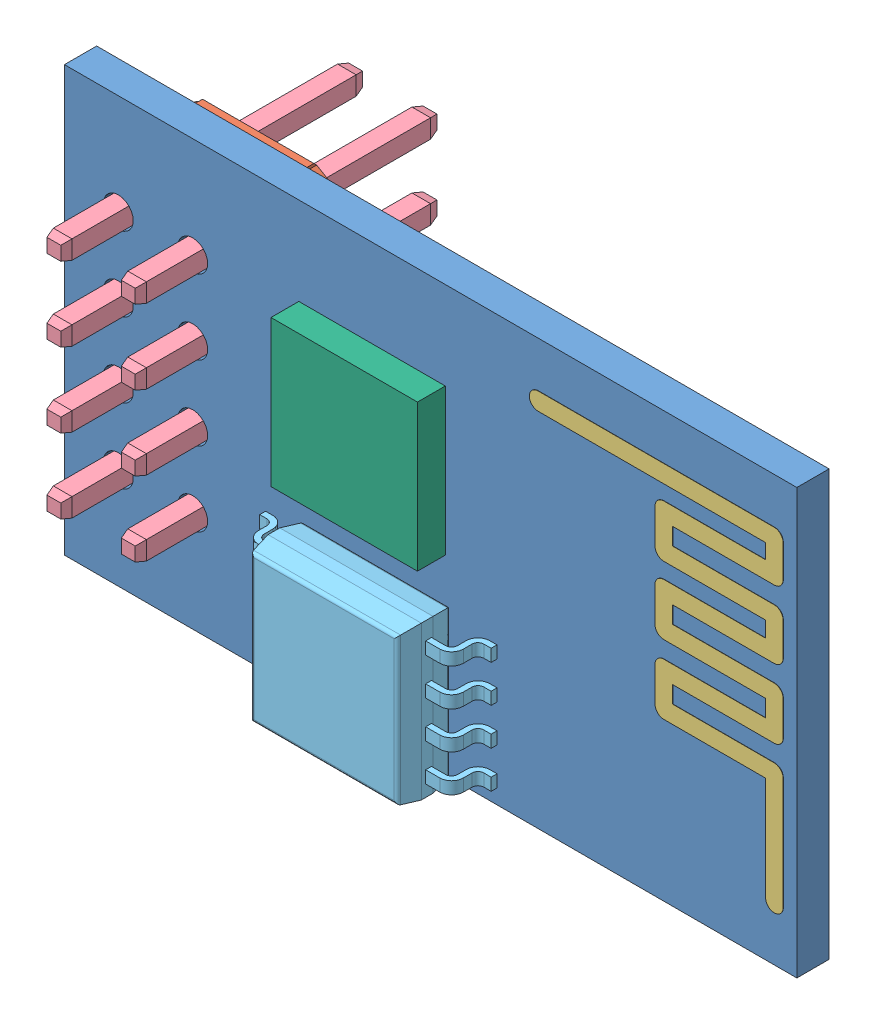
SolidWorks assembly ESP8266-ESP01, configuration Default. Lengths in mm.
Overall size (25 14.5 10.3).
15 component instances, 6 part files, 0 mates.
Components (placement in the parent):
- ESP8266-ESP01.STEP-1: ESP8266-ESP01.STEP [Default] at origin size (25 14.5 10.3)
  - ESP8266-ESP01.stp.STEP-1: ESP8266-ESP01.stp.STEP [Default] at origin size (25 14.5 10.3)
    - Platine.stp.STEP-1: Platine.stp.STEP [Default] at origin size (25 14.5 1.1)
    - PinSockel.stp.STEP-1: PinSockel.stp.STEP [Default] at (1.8391 11.06 0) x (1 0 0) z (0 0 -1) size (5 10.16 2.5)
    - PCB_Antenna.stp.STEP-1: PCB_Antenna.stp.STEP [Default] at (1 16 0.81) x (0 -1 0) z (-1 0 0) size (11.4 0.04 8.67)
    - Pin_Stiftleiste.stp.STEP-1: Pin_Stiftleiste.stp.STEP [Default] at (1.8391 3.44 0) x (-1 0 0) z (0 0 -1) size (0.64 0.64 10.3)
    - Pin_Stiftleiste.stp.STEP-2: Pin_Stiftleiste.stp.STEP [Default] at (4.3791 3.44 0) x (-1 0 0) z (0 0 -1) size (0.64 0.64 10.3)
    - Pin_Stiftleiste.stp.STEP-3: Pin_Stiftleiste.stp.STEP [Default] at (1.8391 5.98 0) x (-1 0 0) z (0 0 -1) size (0.64 0.64 10.3)
    - Pin_Stiftleiste.stp.STEP-4: Pin_Stiftleiste.stp.STEP [Default] at (4.3791 5.98 0) x (-1 0 0) z (0 0 -1) size (0.64 0.64 10.3)
    - Pin_Stiftleiste.stp.STEP-5: Pin_Stiftleiste.stp.STEP [Default] at (1.8391 8.52 0) x (-1 0 0) z (0 0 -1) size (0.64 0.64 10.3)
    - Pin_Stiftleiste.stp.STEP-6: Pin_Stiftleiste.stp.STEP [Default] at (4.3791 8.52 0) x (-1 0 0) z (0 0 -1) size (0.64 0.64 10.3)
    - Pin_Stiftleiste.stp.STEP-7: Pin_Stiftleiste.stp.STEP [Default] at (1.8391 11.06 0) x (-1 0 0) z (0 0 -1) size (0.64 0.64 10.3)
    - Pin_Stiftleiste.stp.STEP-8: Pin_Stiftleiste.stp.STEP [Default] at (4.3791 11.06 0) x (-1 0 0) z (0 0 -1) size (0.64 0.64 10.3)
    - SerialFlashMem.stp.STEP-1: SerialFlashMem.stp.STEP [Default] at (8.2 0.1 1.1) size (7.9 5.23 1.95)
    - ESP8266EX.stp.STEP-1: ESP8266EX.stp.STEP [Default] at (8 6.5 1.1) size (5 5 0.95)
